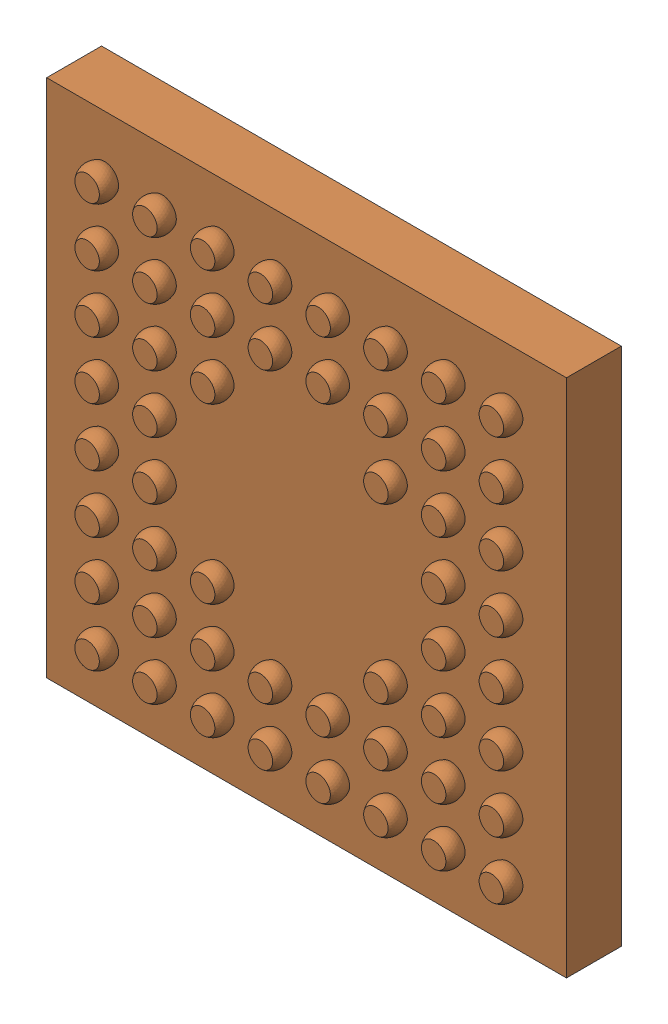
SolidWorks assembly 200020BA-PCB ASSEMBLY EC750C SENSOR-with sensor, configuration Default. Lengths in mm.
Overall size (9 9 1.25).
3 component instances, 2 part files, 0 mates.
Components (placement in the parent):
- 220046-MICRON MT9V022177ATC-1: 220046-MICRON MT9V022177ATC [Default] at (0 0 -0.3) x (1 0 0) z (0 0 -1) size (9 9 1.25)
  - MT9V022 WINDOW-1: MT9V022 WINDOW [Default] at (0 0 0.55) size (6.7 6.7 0.4)
  - MT9V022 PACKAGE-1: MT9V022 PACKAGE [Default] at origin size (9 9 1.25)
